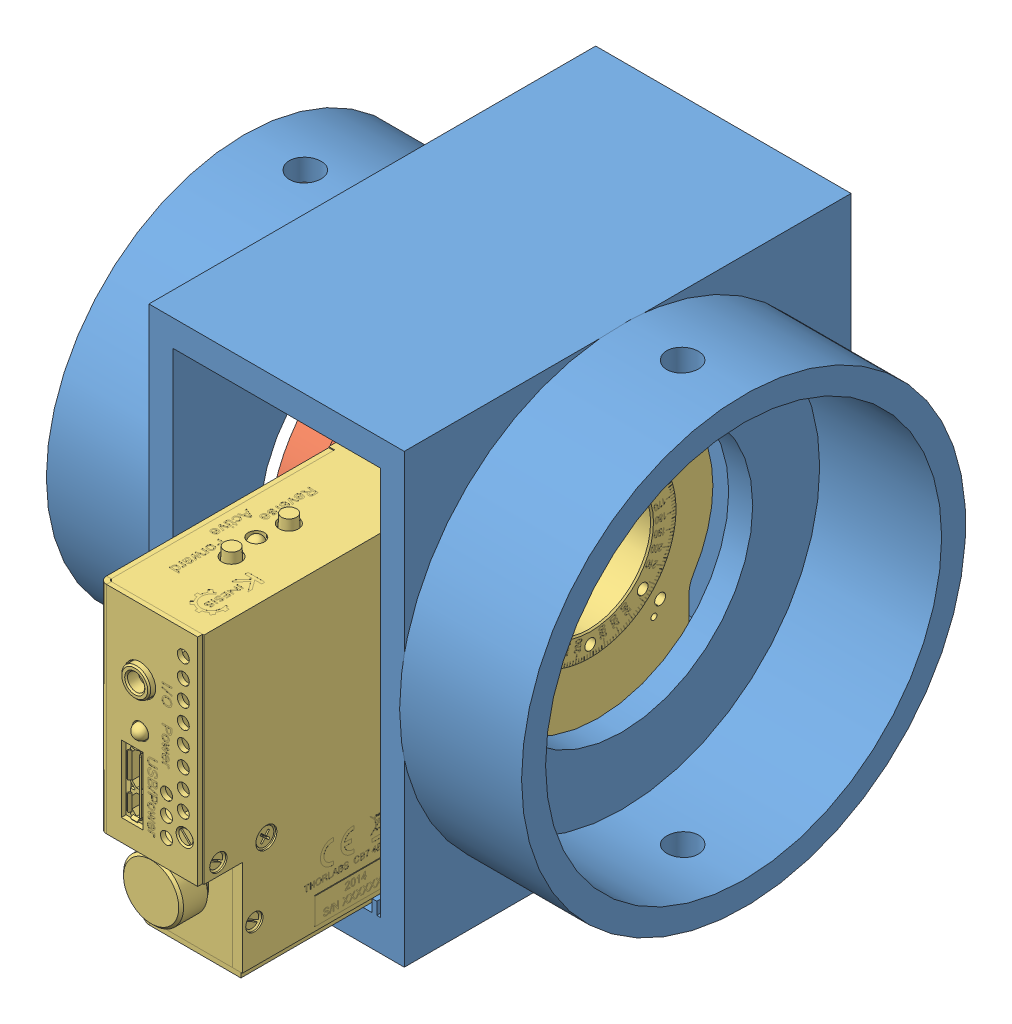
SolidWorks assembly Assem1, configuration Default. Lengths in mm.
Overall size (103.98 93.27 130.19).
3 component instances, 3 part files, 5 mates.
Components (placement in the parent):
- calibration_unit_main-1: calibration_unit_main [Default] at (40.8656 12.9682 56.7202) x (0 0 -1) z (1 0 0) size (95.55 93.27 103.98)
- polariser_rotation_stage-2: polariser_rotation_stage [Default] at (29.0464 60.4199 89.1731) x (0 0 -1) z (0 -1 0) size (56.39 15.49 55.93)
- waveplate_retarder_mount-3: waveplate_retarder_mount [Default] at (47.4244 60.7432 89.1731) x (0 0 1) z (1 0 0) size (108.42 67.89 21.45)
Mates (geometry in assembly coordinates):
- Parallel2: parallel anti-aligned: plane of calibration_unit_main-1 through (40.8656 20.7432 56.7202) normal (0 1 0); plane of waveplate_retarder_mount-3 through (59.4244 20.7432 89.1731) normal (0 -1 0)
- Concentric3: concentric anti-aligned: circle of calibration_unit_main-1; circle of waveplate_retarder_mount-3
- Coincident4: coincident anti-aligned: plane of calibration_unit_main-1 through (40.8656 20.7432 56.7202) normal (0 1 0); plane of waveplate_retarder_mount-3 through (59.4244 20.7432 89.1731) normal (0 -1 0)
- Tangent9: tangent aligned: cylinder of calibration_unit_main-1 through (66.4244 59.9932 89.1731) axis (-1 0 0) radius 27.305; plane of polariser_rotation_stage-2 through (21.2994 32.6882 95.5231) normal (0 -1 0)
- Concentric4: concentric anti-aligned: cylinder of calibration_unit_main-1 through (28.5384 33.0115 89.1731) axis (0 1 0) radius 2.7051; cylinder of polariser_rotation_stage-2 through (28.5384 32.6882 89.1731) axis (0 -1 0) radius 1.7272
